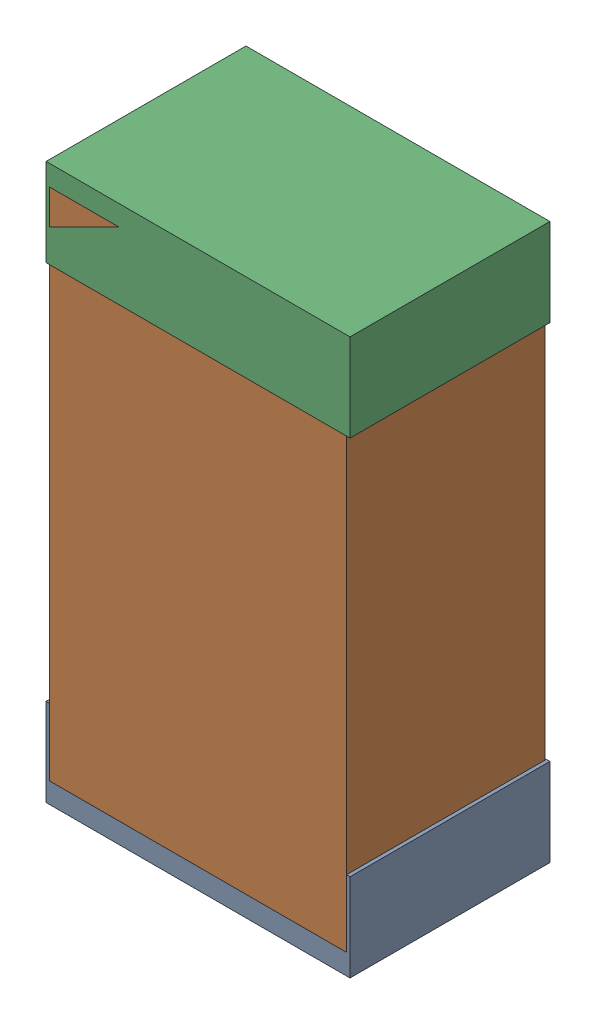
SolidWorks assembly R46Kanaloa_v2.0.0_Motor, configuration Default. Lengths in mm.
Overall size (1.3 2.38 0.85).
6 component instances, 2 part files, 0 mates.
Components (placement in the parent):
- 330415056-1: 330415056 [Default] at (53.34 153.627 -1.9574) size (1.3 0.38 0.85)
  - Extruded_2-1: Extruded_2 [Default] at origin size (1.3 0.38 0.85)
- 334787376-1: 334787376 [Default] at (53.34 154.627 -1.9524) size (1.27 2.2 0.85)
  - Extruded_16-1: Extruded_16 [Default] at origin size (1.27 2.2 0.85)
- 330415056-2: 330415056 [Default] at (53.34 155.627 -1.9574) size (1.3 0.38 0.85)
  - Extruded_2-1: Extruded_2 [Default] at origin size (1.3 0.38 0.85)
